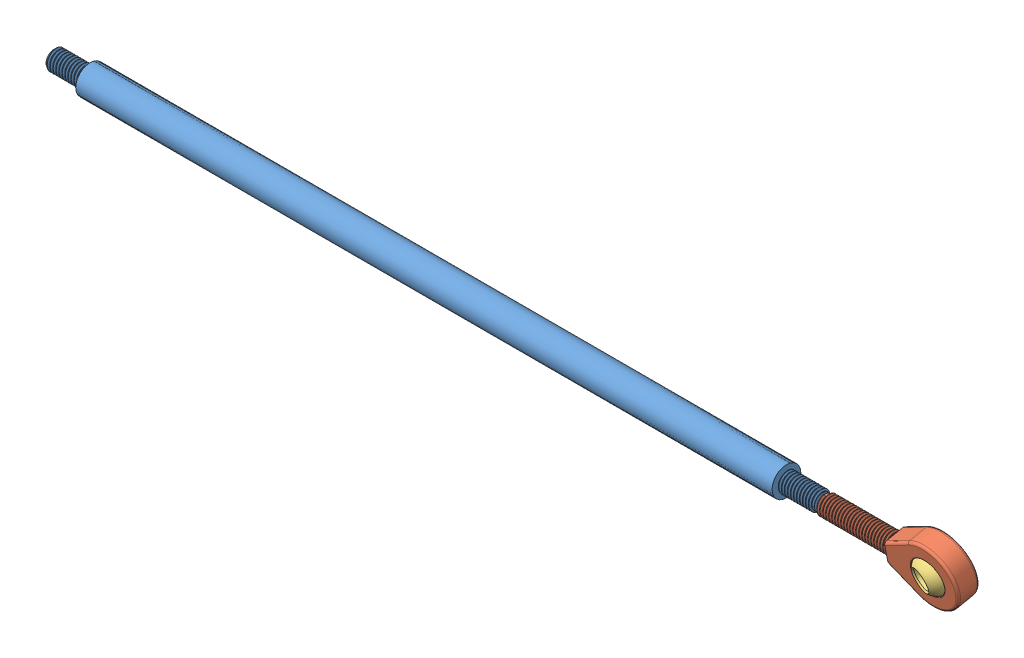
SolidWorks assembly Сборка4, configuration По умолчанию. Lengths in mm.
Overall size (380.71 28.18 23.08).
4 component instances, 3 part files, 2 mates.
Components (placement in the parent):
- Тяга подъема навески 320мм-1: Тяга подъема навески 320мм [По умолчанию] at origin size (320 12 12)
- Шарнир 8-8-30-1: Шарнир 8-8-30 [По умолчанию] at (208.2058 0 0) x (0 0.97988 0.199589) z (0 0.199589 -0.97988) size (25 59.71 18.46)
  - Тело 16х8-1: Тело 16х8 [По умолчанию] at origin size (25 59.71 9.05)
  - Шар 16х8-1: Шар 16х8 [По умолчанию] at (-0.1686 0 -0.0151) x (-0.943748 -0.285871 0.166187) z (0.097464 0.239767 0.965926) size (16 16 13.08)
Mates (geometry in assembly coordinates):
- Концентричный1: concentric: circle of Тяга подъема навески 320мм-1; circle of Шарнир 8-8-30-1/Тело 16х8-1
- Расстояние1: distance = 1 mm: plane of Тяга подъема навески 320мм-1 through (160 3.375 0) normal (1 0 0); plane of Шарнир 8-8-30-1/Тело 16х8-1 through (161 0 0) normal (-1 0 0)
